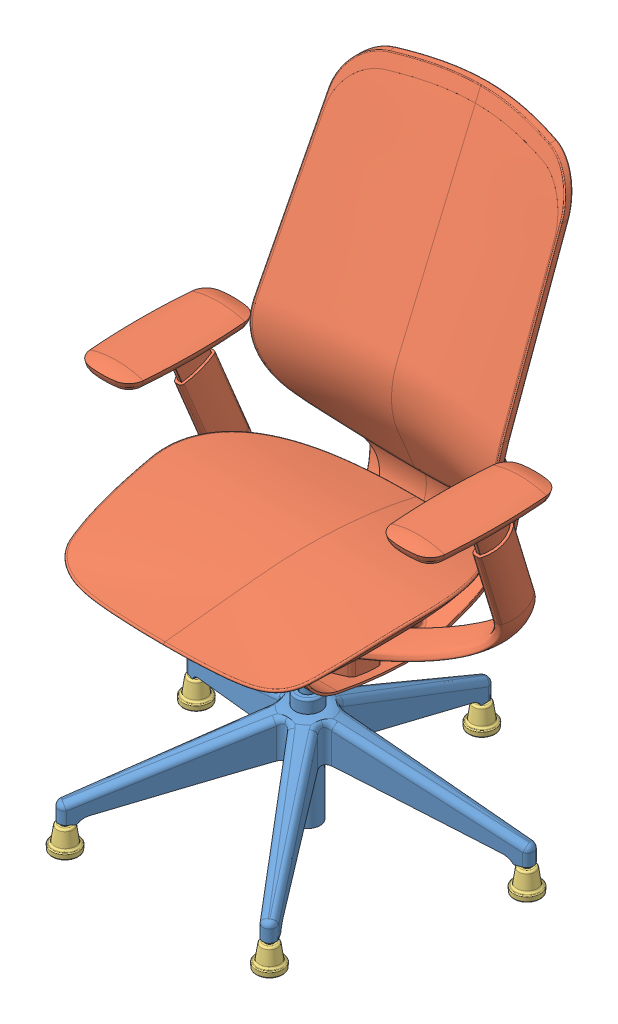
SolidWorks assembly Karman_004a, configuration Défaut. Lengths in mm.
Overall size (707.22 1096.38 672.6).
7 component instances, 3 part files, 9 mates.
Components (placement in the parent):
- Karman_202-1: Karman_202 [Défaut] at (0 208 0) size (667.01 284 635.64)
- Karman_101a-1: Karman_101a [Défaut] at (0 450 0) size (698.88 800.82 666.88)
- Karman_211-1: Karman_211 [Défaut] at (0 50 -337.358) x (0 0 1) z (-1 0 0) size (52 62 52)
- Karman_211-2: Karman_211 [Défaut] at (-320.8465 50 -104.2493) x (0.951057 0 0.309017) z (-0.309017 0 0.951057) size (52 62 52)
- Karman_211-3: Karman_211 [Défaut] at (-198.294 50 272.9283) x (0.587785 0 -0.809017) z (0.809017 0 0.587785) size (52 62 52)
- Karman_211-4: Karman_211 [Défaut] at (198.294 50 272.9283) x (-0.587785 0 -0.809017) z (0.809017 0 -0.587785) size (52 62 52)
- Karman_211-5: Karman_211 [Défaut] at (320.8465 50 -104.2493) x (-0.951057 0 0.309017) z (-0.309017 0 -0.951057) size (52 62 52)
Mates (geometry in assembly coordinates):
- Coïncidente1: coincident aligned: plane of Karman_101a-1 through (0 450 0) normal (1 0 0)
- Coïncidente2: coincident aligned: plane of Karman_101a-1 through (0 450 0) normal (0 0 1)
- Coïncidente3: coincident anti-aligned: plane of Chair-4_202-1 through (0 298 14) normal (0 1 0); plane of Karman_101a-1 through (-27.0711 298 27.0711) normal (0 -1 0)
- Coaxiale1: concentric anti-aligned: circle of Karman_202-1; circle of Karman_211-1
- Parallèle1: parallel aligned: plane of Karman_211-1 through (0 50 -337.358) normal (0 0 1)
- Coïncidente5: coincident aligned: plane of Chair-4_202-1 through (0 208 0) normal (0 0 1)
- Coïncidente6: coincident aligned: plane of Chair-4_202-1 through (0 208 0) normal (1 0 0)
- Distance1: distance = 208 mm aligned: plane of Chair-4_202-1 through (0 208 0) normal (0 1 0)
- Coïncidente8: coincident anti-aligned: plane of Karman_202-1 through (205.7248 50 -283.1559) normal (0 -1 0); plane of Karman_211-1 through (8 50 -337.358) normal (0 1 0)
